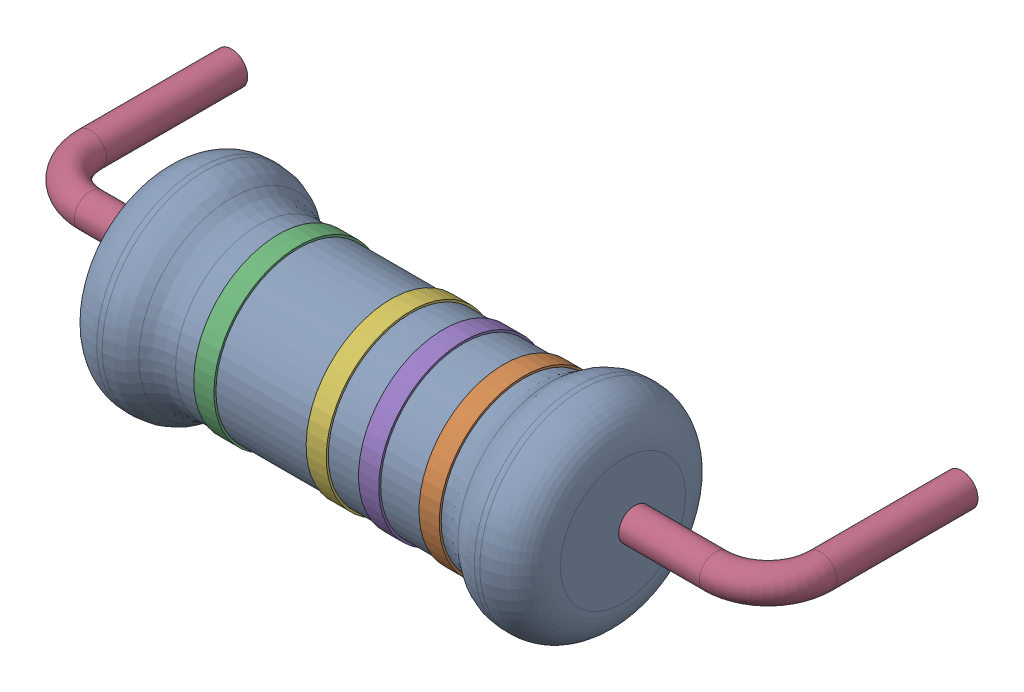
SolidWorks assembly R5.step, configuration Default. Lengths in mm.
Overall size (18.91 5.72 7.96).
7 component instances, 6 part files, 0 mates.
Components (placement in the parent):
- Res_Yageo_KNP100JR-73-22R_eec.step-1: Res_Yageo_KNP100JR-73-22R_eec.step [Default] at (58.547 72.39 0) x (-1 0 0) z (0 0 1) size (18.91 5.72 7.96)
  - 1.step-1: 1.step [Default] at (0 0 2.55) size (11.5 5.1 5.1)
  - 2.step-1: 2.step [Default] at (-3.2931 0 2.55) x (0 0 -1) z (1 0 0) size (4.2 4.2 0.5)
  - 3.step-1: 3.step [Default] at (2.7931 0 2.55) x (0 -0.492137 0.870518) z (-1 0 0) size (4.2 4.2 0.5)
  - 4.step-1: 4.step [Default] at (0 0 -2.55) size (18.91 0.8 5.21)
  - 5.step-1: 5.step [Default] at (-1.7931 0 2.55) x (0 0 -1) z (1 0 0) size (4.2 4.2 0.5)
  - 6.step-1: 6.step [Default] at (0.0069 0 2.55) x (0 -0.017206 0.999852) z (-1 0 0) size (4.2 4.2 0.5)
